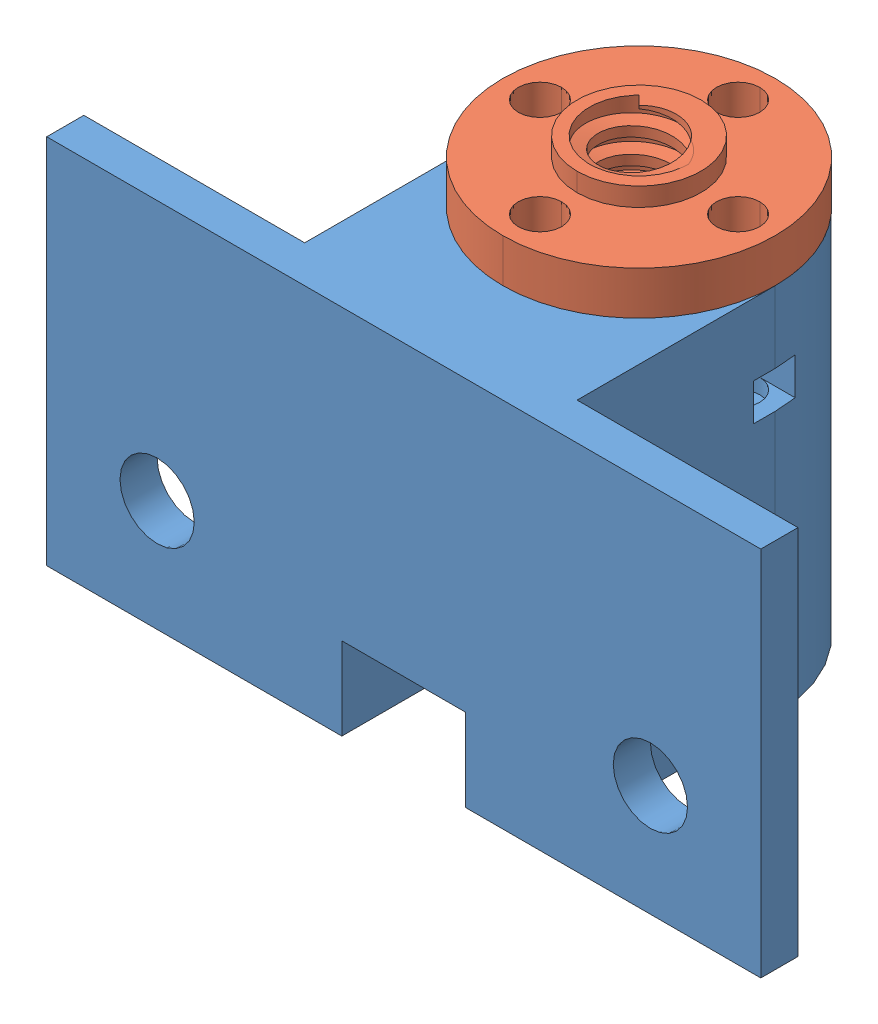
SolidWorks assembly con_truot_1, configuration Default. Lengths in mm.
Overall size (57.67 35.02 30).
2 component instances, 2 part files, 3 mates.
Components (placement in the parent):
- goi_do_dai - Copy-1: goi_do_dai - Copy [Default] at (21.2729 18.5849 52.2178) size (57.67 30 30)
- Leadscrew nut M8 step2mm by Taitran Technic1-1: Leadscrew nut M8 step2mm by Taitran Technic1 [Default] at (21.2729 48.5849 48.2178) size (22 15.03 22)
Mates (geometry in assembly coordinates):
- Concentric3: concentric: cylinder of goi_do_dai - Copy-1 through (21.2729 8.5849 48.2178) axis (0 1 0) radius 4; cylinder of Leadscrew nut M8 step2mm by Taitran Technic1-1 through (21.2729 38.5849 48.2178) axis (0 1 0) radius 5
- Coincident6: coincident anti-aligned: plane of goi_do_dai - Copy-1 through (21.2729 48.5849 52.2178) normal (0 1 0); plane of Leadscrew nut M8 step2mm by Taitran Technic1-1 through (21.2729 48.5849 48.2178) normal (0 -1 0)
- Concentric4: concentric anti-aligned: cylinder of goi_do_dai - Copy-1 through (13.2729 38.5849 48.2178) axis (0 1 0) radius 1.75; cylinder of Leadscrew nut M8 step2mm by Taitran Technic1-1 through (13.2729 52.0849 48.2178) axis (0 -1 0) radius 1.75
